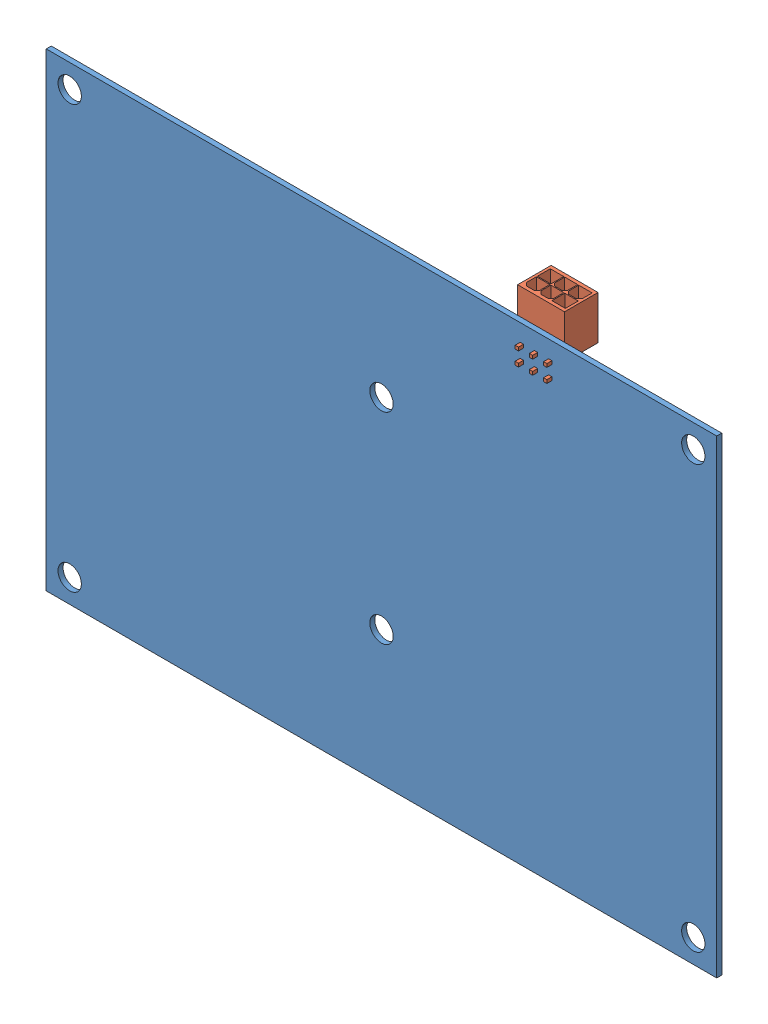
SolidWorks assembly Heated bed assy, configuration По умолчанию. Lengths in mm.
Overall size (200 147.89 14.8).
2 component instances, 2 part files, 1 mates.
Components (placement in the parent):
- Heated bed-1: Heated bed [По умолчанию] at origin size (200 140 1.5)
- MF-6 MRA-1: MF-6 MRA [По умолчанию] at (46.0967 64.8875 -5) x (0 0 -1) z (1 0 0) size (14.8 18.15 14)
Mates (geometry in assembly coordinates):
- Совпадение1: coincident anti-aligned: plane of Heated bed-1 through (-100 70 0) normal (0 0 -1); plane of MF-6 MRA-1 through (46.0967 77.8875 0) normal (0 0 1)
